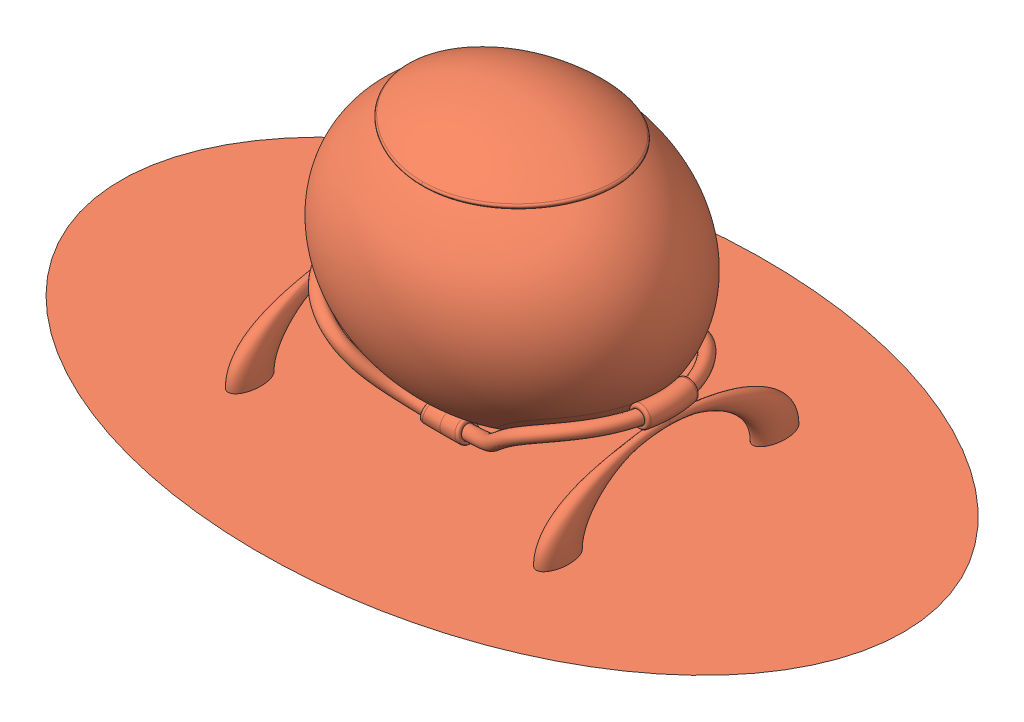
SolidWorks assembly Martian in a Jar, configuration Default. Lengths in mm.
Overall size (458.96 193.78 296.85).
2 component instances, 2 part files, 2 mates.
Components (placement in the parent):
- Alien Head-1: Alien Head [Default] at (20.5307 -38.9423 23.258) x (0.979398 0.191389 -0.064417) z (-0.009549 0.362527 0.931924) size (232.43 130.33 83.91)
- Globe-1: Globe [Default] at (0 26.2056 0) size (458.96 160.65 296.85)
Mates (geometry in assembly coordinates):
- Coincident3: coincident aligned: plane of Globe-1 through (0 26.2056 0) normal (1 0 0)
- Coincident4: coincident aligned: unknown of Globe-1
